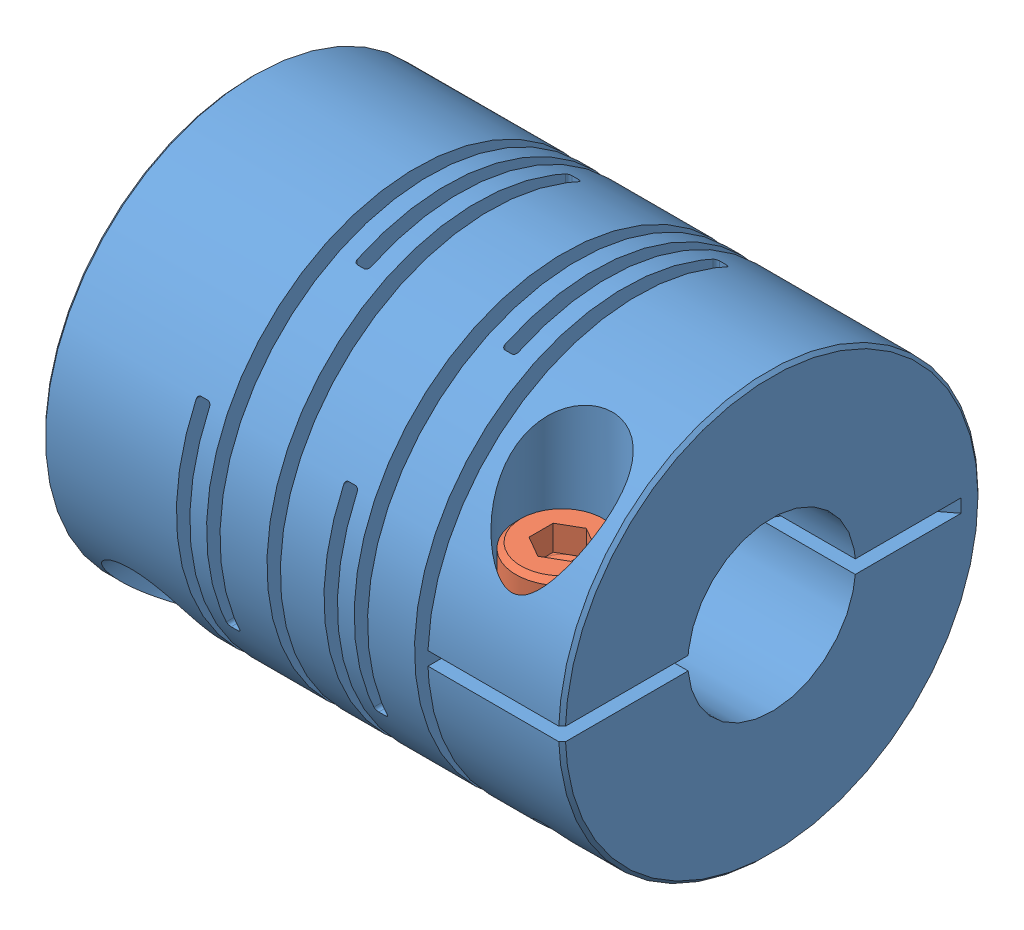
SolidWorks assembly B9_GSACL25-8-10, configuration Default. Lengths in mm.
Overall size (31.01 25 25).
3 component instances, 2 part files, 0 mates.
Components (placement in the parent):
- GSACL25-8-10_b-1: GSACL25-8-10_b [Default] at origin size (31.01 25 25)
- BOLT3-10-1: BOLT3-10 [Default] at (27 3 8.5) x (0 -1 0) z (-1 0 0) size (13 5.5 5.5)
- BOLT3-10-2: BOLT3-10 [Default] at (4 -8.5 3) x (0 0 -1) z (-1 0 0) size (13 5.5 5.5)
